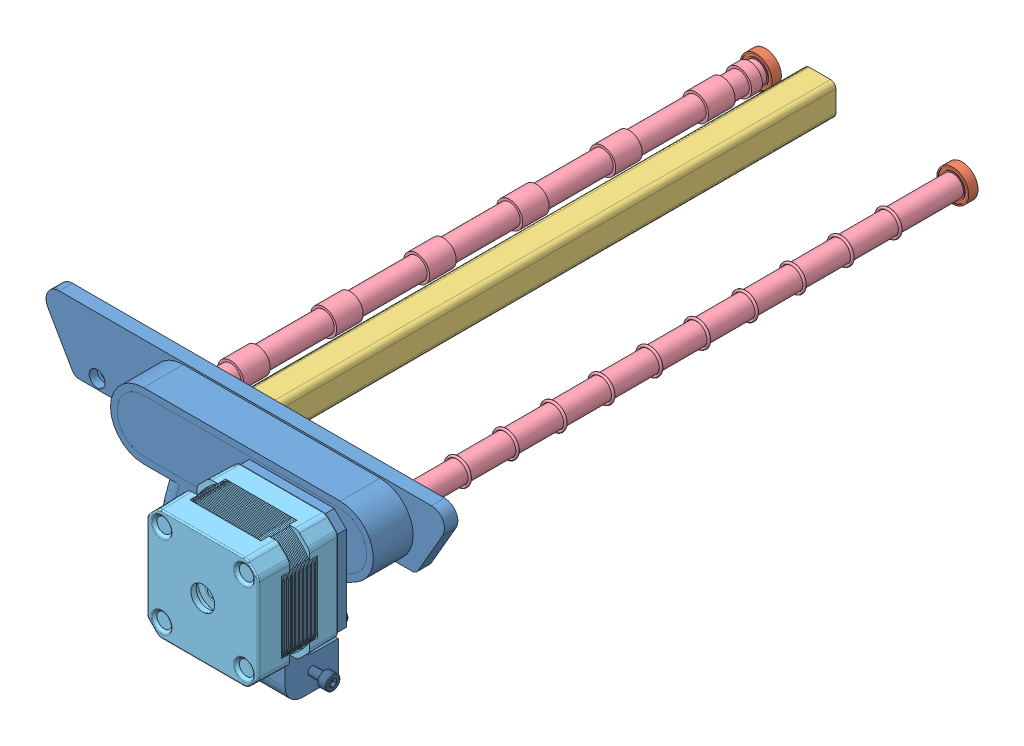
SolidWorks assembly Paper feeding, configuration Default. Lengths in mm.
Overall size (150 78.25 268).
22 component instances, 10 part files, 43 mates.
Components (placement in the parent):
- Side block-1: Side block [Default] at (58.8749 0.6785 220.0612) size (150 78.25 23.5)
- MR128ZZ bearing-1: MR128ZZ bearing [Default] at (5.5949 7.5785 7.8112) size (12 12 3.5)
- MR128ZZ bearing-2: MR128ZZ bearing [Default] at (79.5949 7.5785 7.8112) size (12 12 3.5)
- MR128ZZ bearing-3: MR128ZZ bearing [Default] at (5.5949 7.5785 221.8112) size (12 12 3.5)
- MR128ZZ bearing-4: MR128ZZ bearing [Default] at (79.5949 7.5785 221.8112) size (12 12 3.5)
- Counter block-1: Counter block [Milled holes] at (25.5949 9.1785 5.5612) x (0 -1 0) z (0 0 1) size (12 12 218.5)
- Driving rod-1: Driving rod [Feed roller] at (5.5949 7.5785 6.0612) size (9.8 9.8 229.5)
- Driving rod-2: Driving rod [Outfeed roller] at (79.5949 7.5785 235.5612) x (-1 0 0) z (0 0 -1) size (9.89 9.89 229.5)
- Stepper motor-1: Stepper motor [Default] at (61.3758 -3.9671 254.5612) x (0 -1 0) z (1 0 0) size (42.8 48.5 42.3)
- 2GT driving pulley-1: 2GT driving pulley [20 short 8mm hole] at (79.5949 7.5785 225.5612) x (1 0 0) z (0 -1 0) size (16 10 16)
- 2GT driving pulley-2: 2GT driving pulley [20 short 8mm hole] at (5.5949 7.5785 225.5612) x (1 0 0) z (0 -1 0) size (16 10 16)
- 2GT driving pulley-3: 2GT driving pulley [16T short] at (61.3758 -3.9671 226.0612) x (1 0 0) z (0 -1 0) size (13 9.5 13)
- HK050908 bearing-1: HK050908 bearing [Default] at (41.8749 4.6647 227.0612) size (9 9 8)
- Belt^Paper feeding-1: Belt^Paper feeding [Default] at (0 0.2 231.0612) size (87.49 23.76 6) (virtual)
- Shortened shoulder screw-1: Shortened shoulder screw [Default] at (41.8749 4.6647 222.0612) x (1 0 0) z (0 -1 0) size (9 17 9)
- socket head cap screw_din-1: socket head cap screw_din [DIN 912 M3 x 12 --- 12N] at (66.8749 -50.5715 230.0612) x (-1 0 0) z (0 0 -1) size (15 5.5 5.5)
- socket head cap screw_din-2: socket head cap screw_din [DIN 912 M3 x 12 --- 12N] at (66.8749 -19.5715 230.0612) x (-1 0 0) z (0 0 -1) size (15 5.5 5.5)
- socket head cap screw_din-3: socket head cap screw_din [DIN 912 M3 x 10 --- 10N] at (45.8758 11.5329 234.5612) x (0 0 1) z (-1 0 0) size (13 5.5 5.5)
- socket head cap screw_din-4: socket head cap screw_din [DIN 912 M3 x 8 --- 8N] at (76.8758 11.5329 236.0612) x (0 0 1) z (-1 0 0) size (11 5.5 5.5)
- socket head cap screw_din-5: socket head cap screw_din [DIN 912 M3 x 8 --- 8N] at (76.8758 -19.4715 237.0612) x (0 0 1) z (-1 0 0) size (11 5.5 5.5)
- socket head cap screw_din-6: socket head cap screw_din [DIN 912 M3 x 10 --- 10N] at (45.8749 -19.4715 235.5612) x (0 0 1) z (-1 0 0) size (13 5.5 5.5)
- socket head cap screw_din-7: socket head cap screw_din [DIN 912 M3 x 12 --- 12N] at (33.9103 1.2819 243.0612) x (0 0 -1) z (1 0 0) size (15 5.5 5.5)
Mates (geometry in assembly coordinates):
- Concentric1: concentric aligned: cylinder of Side block-1 through (5.5949 7.5785 223.5612) axis (0 0 -1) radius 6; cylinder of MR128ZZ bearing-3 through (5.5949 7.5785 220.0612) axis (0 0 -1) radius 6
- Coincident3: coincident aligned: plane of Side block-1 through (94.5448 3.1785 220.0612) normal (0 0 -1); plane of MR128ZZ bearing-3 through (11.0949 7.5785 220.0612) normal (0 0 -1)
- Concentric2: concentric aligned: cylinder of Side block-1 through (79.5949 7.5785 223.5612) axis (0 0 -1) radius 6; cylinder of MR128ZZ bearing-4 through (79.5949 7.5785 220.0612) axis (0 0 -1) radius 6
- Coincident4: coincident aligned: plane of Side block-1 through (94.5448 3.1785 220.0612) normal (0 0 -1); plane of MR128ZZ bearing-4 through (85.0949 7.5785 220.0612) normal (0 0 -1)
- Concentric3: concentric aligned: cylinder of MR128ZZ bearing-1 through (5.5949 7.5785 6.0612) axis (0 0 -1) radius 4; cylinder of MR128ZZ bearing-3 through (5.5949 7.5785 220.0612) axis (0 0 -1) radius 4
- Distance1: distance = 210.5 mm anti-aligned: plane of Side block-1 through (94.5448 3.1785 220.0612) normal (0 0 -1); plane of Bearing-1 through (11.0949 7.5785 9.5612) normal (0 0 1)
- Coincident5: coincident aligned: plane of MR128ZZ bearing-1 through (11.0949 7.5785 9.5612) normal (0 0 1); plane of MR128ZZ bearing-2 through (85.0949 7.5785 9.5612) normal (0 0 1)
- Concentric4: concentric aligned: cylinder of MR128ZZ bearing-2 through (79.5949 7.5785 6.0612) axis (0 0 -1) radius 4; cylinder of MR128ZZ bearing-4 through (79.5949 7.5785 220.0612) axis (0 0 -1) radius 4
- Concentric5: concentric aligned: cylinder of MR128ZZ bearing-1 through (5.5949 7.5785 6.0612) axis (0 0 -1) radius 4; cylinder of Driving rod-1 through (5.5949 7.5785 235.5612) axis (0 0 -1) radius 4
- Coincident6: coincident aligned: plane of MR128ZZ bearing-1 through (9.5949 7.5785 6.0612) normal (0 0 -1); plane of Driving rod-1 through (5.5949 7.5785 6.0612) normal (0 0 -1)
- Coincident7: coincident anti-aligned: plane of Side block-1 through (29.5949 5.1785 224.0612) normal (0 0 -1); plane of Counter block-1 through (29.5949 13.1785 224.0612) normal (0 0 1)
- Coincident8: coincident anti-aligned: plane of Side block-1 through (19.5949 13.1785 224.0612) normal (1 0 0); plane of Counter block-1 through (19.5949 13.1785 224.0612) normal (-1 0 0)
- Coincident9: coincident anti-aligned: plane of Side block-1 through (29.5949 3.1785 224.0612) normal (0 1 0); plane of Counter block-1 through (29.5949 3.1785 224.0612) normal (0 -1 0)
- Coincident10: coincident aligned: plane of Driving rod-1 through (5.5949 7.5785 6.0612) normal (0 0 -1); plane of Driving rod-2 through (79.5949 7.5785 6.0612) normal (0 0 -1)
- Concentric6: concentric anti-aligned: cylinder of MR128ZZ bearing-2 through (79.5949 7.5785 6.0612) axis (0 0 -1) radius 4; cylinder of Driving rod-2 through (79.5949 7.5785 6.0612) axis (0 0 1) radius 4
- Distance2: distance = 5 mm anti-aligned: plane of Side block-1 through (58.8749 0.6785 225.0612) normal (1 0 0); plane of socket head cap screw_din-1 through (63.8749 -47.8215 230.0612) normal (-1 0 0)
- Concentric7: concentric aligned: cylinder of Side block-1 through (48.8749 -19.5715 230.0612) axis (1 0 0) radius 1.375; cylinder of socket head cap screw_din-2 through (98.6249 -19.5715 230.0612) axis (1 0 0) radius 1.5
- Coincident11: coincident aligned: plane of socket head cap screw_din-1 through (63.8749 -47.8215 230.0612) normal (-1 0 0); plane of socket head cap screw_din-2 through (63.8749 -16.8215 230.0612) normal (-1 0 0)
- Concentric8: concentric aligned: cylinder of Side block-1 through (48.8749 -50.5715 230.0612) axis (1 0 0) radius 1.375; cylinder of socket head cap screw_din-1 through (98.6249 -50.5715 230.0612) axis (1 0 0) radius 1.5
- Coincident14: coincident anti-aligned: plane of Side block-1 through (79.5949 7.5785 227.0612) normal (0 0 1); plane of Shortened shoulder screw-1 through (44.3749 4.6647 227.0612) normal (0 0 -1)
- Concentric11: concentric anti-aligned: cylinder of Side block-1 through (41.8749 4.6647 221.0612) axis (0 0 1) radius 1.75; cylinder of Shortened shoulder screw-1 through (41.8749 4.6647 222.0612) axis (0 0 -1) radius 2.5
- Concentric12: concentric aligned: cylinder of Shortened shoulder screw-1 through (41.8749 4.6647 222.0612) axis (0 0 -1) radius 2.5; cylinder of HK050908 bearing-1 through (41.8749 4.6647 235.0612) axis (0 0 -1) radius 2.5
- Coincident15: coincident anti-aligned: plane of Side block-1 through (79.5949 7.5785 227.0612) normal (0 0 1); plane of HK050908 bearing-1 through (41.8749 4.6647 227.0612) normal (0 0 -1)
- Coincident16: coincident anti-aligned: plane of Side block-1 through (58.8749 0.6785 243.5612) normal (0 0 1); plane of Stepper motor-1 through (61.3758 -3.9671 243.5612) normal (0 0 -1)
- Concentric13: concentric anti-aligned: cylinder of Side block-1 through (45.8758 11.5329 236.5612) axis (0 0 1) radius 1.6; cylinder of Stepper motor-1 through (45.8758 11.5329 248.5612) axis (0 0 -1) radius 1.25
- Concentric14: concentric anti-aligned: cylinder of Side block-1 through (45.8758 11.5329 236.5612) axis (0 0 1) radius 1.6; cylinder of socket head cap screw_din-3 through (45.8758 11.5329 202.8112) axis (0 0 -1) radius 2.75
- Coincident17: coincident anti-aligned: plane of Side block-1 through (45.8758 11.5329 237.5612) normal (0 0 -1); plane of socket head cap screw_din-3 through (45.8758 14.2829 237.5612) normal (0 0 1)
- Concentric15: concentric anti-aligned: cylinder of Side block-1 through (76.8758 11.5329 236.5612) axis (0 0 1) radius 1.6; cylinder of socket head cap screw_din-4 through (76.8758 11.5329 204.3112) axis (0 0 -1) radius 2.75
- Coincident18: coincident anti-aligned: plane of Side block-1 through (76.8758 11.5329 239.0612) normal (0 0 -1); plane of socket head cap screw_din-4 through (76.8758 14.2829 239.0612) normal (0 0 1)
- Concentric16: concentric aligned: cylinder of Side block-1 through (76.8758 -19.4715 241.0612) axis (0 0 -1) radius 1.6; cylinder of socket head cap screw_din-5 through (76.8758 -19.4715 205.3112) axis (0 0 -1) radius 2.75
- Coincident19: coincident anti-aligned: plane of Side block-1 through (58.8749 0.6785 240.0612) normal (0 0 -1); plane of socket head cap screw_din-5 through (76.8758 -16.7215 240.0612) normal (0 0 1)
- Concentric18: concentric anti-aligned: cylinder of Side block-1 through (45.8749 -19.4715 219.5498) axis (0 0 1) radius 1.6; cylinder of socket head cap screw_din-6 through (45.8749 -19.4715 203.8112) axis (0 0 -1) radius 2.75
- Coincident20: coincident anti-aligned: plane of Side block-1 through (139.3749 -45.0715 238.5612) normal (0 0 -1); plane of socket head cap screw_din-6 through (45.8749 -16.7215 238.5612) normal (0 0 1)
- Concentric19: concentric aligned: cylinder of Side block-1 through (33.9103 1.2819 236.5612) axis (0 0 1) radius 1.6; cylinder of socket head cap screw_din-7 through (33.9103 1.2819 274.8112) axis (0 0 1) radius 2.75
- Coincident21: coincident anti-aligned: plane of Side block-1 through (79.5949 7.5785 240.0612) normal (0 0 1); plane of socket head cap screw_din-7 through (33.9103 4.0319 240.0612) normal (0 0 -1)
- Concentric21: concentric aligned: cylinder of Driving rod-1 through (5.5949 7.5785 235.5612) axis (0 0 -1) radius 4; cylinder of 2GT driving pulley-2 through (5.5949 7.5785 225.5612) axis (0 0 -1) radius 4
- Coincident23: coincident aligned: plane of Driving rod-1 through (5.5949 7.5785 235.5612) normal (0 0 1); plane of 2GT driving pulley-2 through (13.5949 7.5785 235.5612) normal (0 0 1)
- Width4: width aligned: plane of 2GT driving pulley-2 through (13.5949 7.5785 227.5612) normal (0 0 1); plane of 2GT driving pulley-2 through (11.9611 7.5785 234.5612) normal (0 0 -1); plane of Belt^Paper feeding-1 through (5.5949 7.5785 234.0612) normal (0 0 1); plane of Belt^Paper feeding-1 through (5.5949 7.5785 228.0612) normal (0 0 -1)
- Concentric22: concentric aligned: cylinder of 2GT driving pulley-2 through (5.5949 7.5785 225.5612) axis (0 0 -1) radius 6.3662; cylinder of Belt^Paper feeding-1 through (5.5949 7.5785 234.0612) axis (0 0 -1) radius 6.7462
- Concentric23: concentric anti-aligned: cylinder of Driving rod-2 through (79.5949 7.5785 6.0612) axis (0 0 1) radius 4; cylinder of 2GT driving pulley-1 through (79.5949 7.5785 225.5612) axis (0 0 -1) radius 4
- Coincident24: coincident aligned: plane of Driving rod-2 through (79.5949 7.5785 235.5612) normal (0 0 1); plane of 2GT driving pulley-1 through (87.5949 7.5785 235.5612) normal (0 0 1)
- Concentric24: concentric anti-aligned: cylinder of Stepper motor-1 through (61.3758 -3.9671 244.0612) axis (0 0 1) radius 2.5; cylinder of 2GT driving pulley-3 through (61.3758 -3.9671 226.0612) axis (0 0 -1) radius 2.5
- Coincident25: coincident aligned: plane of 2GT driving pulley-1 through (85.9611 7.5785 234.5612) normal (0 0 -1); plane of 2GT driving pulley-3 through (66.4688 -3.9671 234.5612) normal (0 0 -1)
